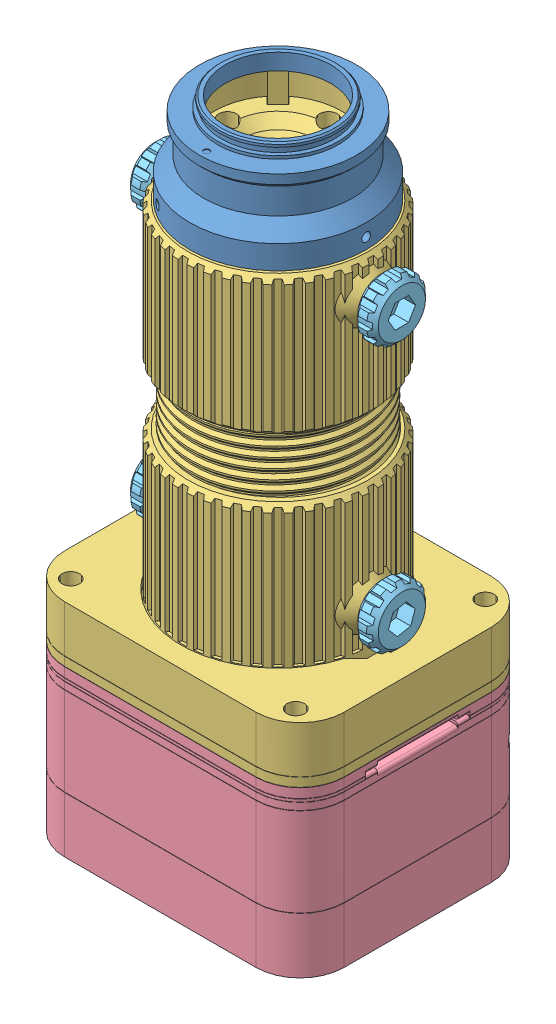
SolidWorks assembly scanner, configuration Výchozí. Lengths in mm.
Overall size (95 220.5 80).
9 component instances, 6 part files, 23 mates.
Components (placement in the parent):
- layout-1: layout [Výchozí] x (1 0 0) z (0 -1 0) size (43.27 43.27 182.46) (hidden)
- MFT_to_T2_gutted-1: MFT_to_T2_gutted [Výchozí] x (1 0 0) z (0 -1 0) size (60 60 30.5)
- lens-1: lens [Výchozí] at (0 -59.2222 0) x (-1 0 0) z (0 1 0) size (12.5 12.5 4.3)
- tube_center-1: tube_center [Výchozí] at (0 -20.46 0) x (1 0 0) z (0 -1 0) size (95 80 158.9)
- lightbox-1: lightbox [Výchozí] at (0 -182.4592 0) size (95 56 80)
- screw_handle_m5-1: screw_handle_m5 [Výchozí] at (35.1 -57.96 0) x (0 -1 0) z (0 0 1) size (19.77 7 19.77)
- screw_handle_m5-2: screw_handle_m5 [Výchozí] at (35.1 -148.16 0) x (0 -0.332152 -0.943226) z (0 -0.943226 0.332152) size (19.77 7 19.77)
- screw_handle_m5-3: screw_handle_m5 [Výchozí] at (-35.1 -148.16 0) x (0 1 0) z (0 0 1) size (19.77 7 19.77)
- screw_handle_m5-4: screw_handle_m5 [Výchozí] at (-35.1 -57.96 0) x (0 1 0) z (0 0 1) size (19.77 7 19.77)
Mates (geometry in assembly coordinates):
- Soustředná2: concentric aligned: cylinder of MFT_to_T2_gutted-1 through (0 0 0) axis (0 1 0) radius 24.5; cylinder of tube_center-1 through (0 -20.46 0) axis (0 1 0) radius 24.25
- Sjednocená8: coincident anti-aligned: plane of MFT_to_T2_gutted-1 through (0 -20.46 17.955) normal (0 -1 0); plane of tube_center-1 through (14.4957 -20.46 -18.0312) normal (0 1 0)
- Sjednocená10: coincident aligned: plane of layout-1 through (0 0 0) normal (0 0 1); plane of assembly through (0 0 0) normal (0 0 1)
- Sjednocená11: coincident aligned: plane of layout-1; plane of assembly through (0 0 0) normal (1 0 0)
- Sjednocená12: coincident anti-aligned: plane of layout-1 through (0 0 0) normal (0 -1 0); plane of assembly through (0 0 0) normal (0 1 0)
- Sjednocená13: coincident aligned: plane of layout-1 through (0 0 0) normal (0 -1 0); plane of MFT_to_T2_gutted-1 through (0 0 0) normal (0 -1 0)
- Sjednocená14: coincident aligned: plane of layout-1; plane of MFT_to_T2_gutted-1
- Soustředná3: concentric anti-aligned: line of layout-1 through (0 0 0) axis (0 -1 0); cylinder of MFT_to_T2_gutted-1 through (0 0 0) axis (0 1 0) radius 17.955
- Soustředná5: concentric aligned: cylinder of MFT_to_T2_gutted-1 through (30.001 -41.71 0) axis (-1 0 0) radius 1.5; cylinder of tube_center-1 through (30 -41.71 0) axis (-1 0 0) radius 1.6
- Soustředná6: concentric aligned: cylinder of lens-1 through (0 6.1317 0) axis (0 1 0) radius 6.25; cylinder of tube_center-1 through (0 -20.46 0) axis (0 1 0) radius 6.4
- Tečná2: tangent aligned: sphere of lens-1; sphere of tube_center-1
- Rovnoběžná1: parallel anti-aligned: plane of lens-1; plane of assembly through (0 0 0) normal (1 0 0)
- Sjednocená16: coincident: point of layout-1; point of lightbox-1
- Rovnoběžná2: parallel aligned: plane of lightbox-1 through (0 -182.4592 0) normal (0 1 0); plane of assembly through (0 0 0) normal (0 1 0)
- Sjednocená18: coincident aligned: plane of lightbox-1 through (0 -182.4592 0) normal (0 0 1); plane of assembly through (0 0 0) normal (0 0 1)
- Sjednocená19: coincident anti-aligned: plane of tube_center-1 through (35.1 -52.96 0) normal (1 0 0); plane of screw_handle_m5-1 through (35.1 -57.96 -2.75) normal (-1 0 0)
- Soustředná7: concentric aligned: cylinder of tube_center-1 through (47.5 -57.96 0) axis (-1 0 0) radius 3; cylinder of screw_handle_m5-1 through (35.1 -57.96 0) axis (-1 0 0) radius 2.75
- Sjednocená20: coincident anti-aligned: plane of tube_center-1 through (35.1 -143.16 0) normal (1 0 0); plane of screw_handle_m5-2 through (35.1 -145.5661 -0.9134) normal (-1 0 0)
- Soustředná8: concentric aligned: cylinder of tube_center-1 through (47.5 -148.16 0) axis (-1 0 0) radius 3; cylinder of screw_handle_m5-2 through (35.1 -148.16 0) axis (-1 0 0) radius 2.75
- Sjednocená21: coincident anti-aligned: plane of tube_center-1 through (-35.1 -143.16 0) normal (-1 0 0); plane of screw_handle_m5-3 through (-35.1 -148.16 -2.75) normal (1 0 0)
- Soustředná9: concentric anti-aligned: cylinder of tube_center-1 through (47.5 -148.16 0) axis (-1 0 0) radius 3; cylinder of screw_handle_m5-3 through (-35.1 -148.16 0) axis (1 0 0) radius 2.75
- Sjednocená22: coincident anti-aligned: plane of tube_center-1 through (-35.1 -52.96 0) normal (-1 0 0); plane of screw_handle_m5-4 through (-35.1 -57.96 -2.75) normal (1 0 0)
- Soustředná10: concentric anti-aligned: cylinder of tube_center-1 through (47.5 -57.96 0) axis (-1 0 0) radius 3; cylinder of screw_handle_m5-4 through (-35.1 -57.96 0) axis (1 0 0) radius 2.75
